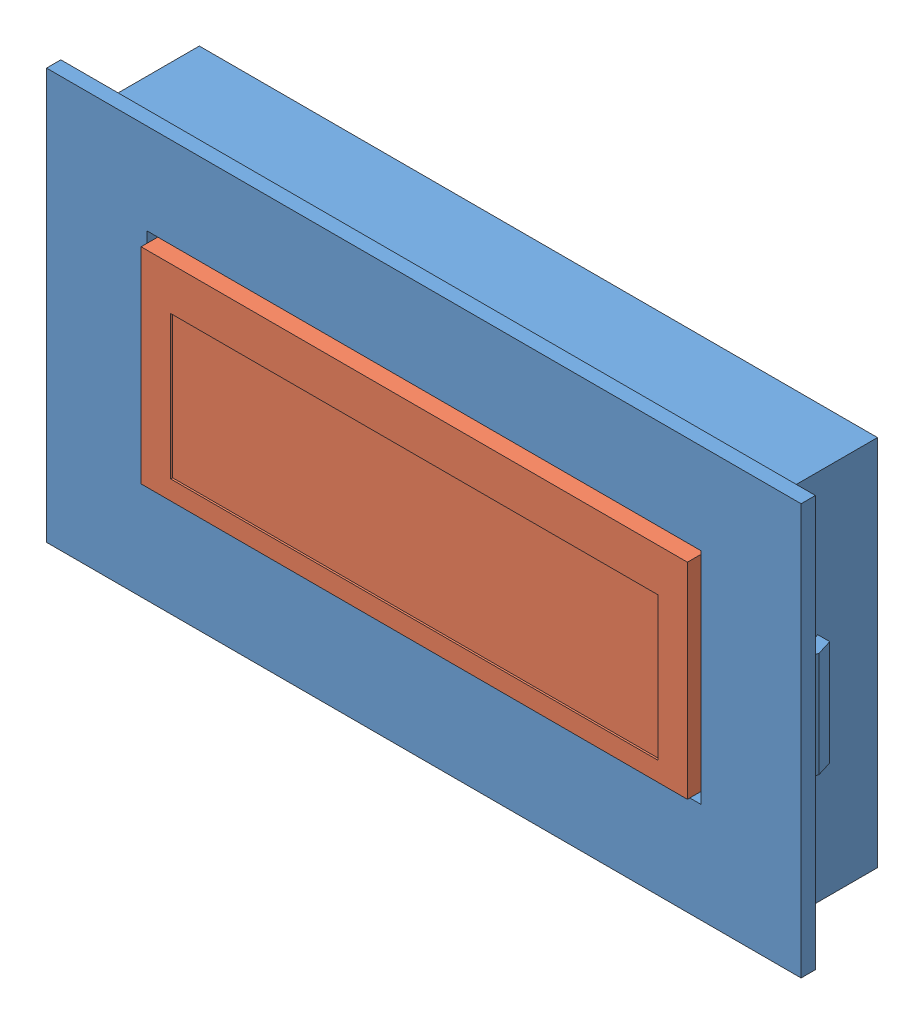
SolidWorks assembly WindingCTRL1, configuration По умолчанию. Lengths in mm.
Overall size (79 43 13).
2 component instances, 2 part files, 6 mates.
Components (placement in the parent):
- LCDHolder-1: LCDHolder [По умолчанию] x (-1 0 0) z (0 0 -1) size (79 43 12)
- PC1602ARH-VWW-1: PC1602ARH-VWW [По умолчанию] at (0 0 -4) size (66.2 26 9.5)
Mates (geometry in assembly coordinates):
- Совпадение7: coincident: plane of LCDHolder-1 through (0 0 0) normal (0 0 1); plane of assembly through (0 0 0) normal (0 0 1)
- Совпадение8: coincident: plane of assembly through (0 0 0) normal (1 0 0); plane of LCDHolder-1 through (0 0 0) normal (-1 0 0)
- Совпадение9: coincident: plane of LCDHolder-1 through (0 0 0) normal (0 1 0); plane of assembly through (0 0 0) normal (0 1 0)
- Совпадение10: coincident: plane of LCDHolder-1 through (0 0 0) normal (-1 0 0); plane of PC1602ARH-VWW-1 through (0 0 -4) normal (1 0 0)
- Совпадение11: coincident: plane of LCDHolder-1 through (0 0 -4) normal (0 0 -1); plane of PC1602ARH-VWW-1 through (0 0 -4) normal (0 0 1)
- Расстояние2: distance = 0.75 mm: plane of PC1602ARH-VWW-1 through (-28.6 11.25 1) normal (0 1 0); plane of LCDHolder-1 through (29 12 0) normal (0 -1 0)
